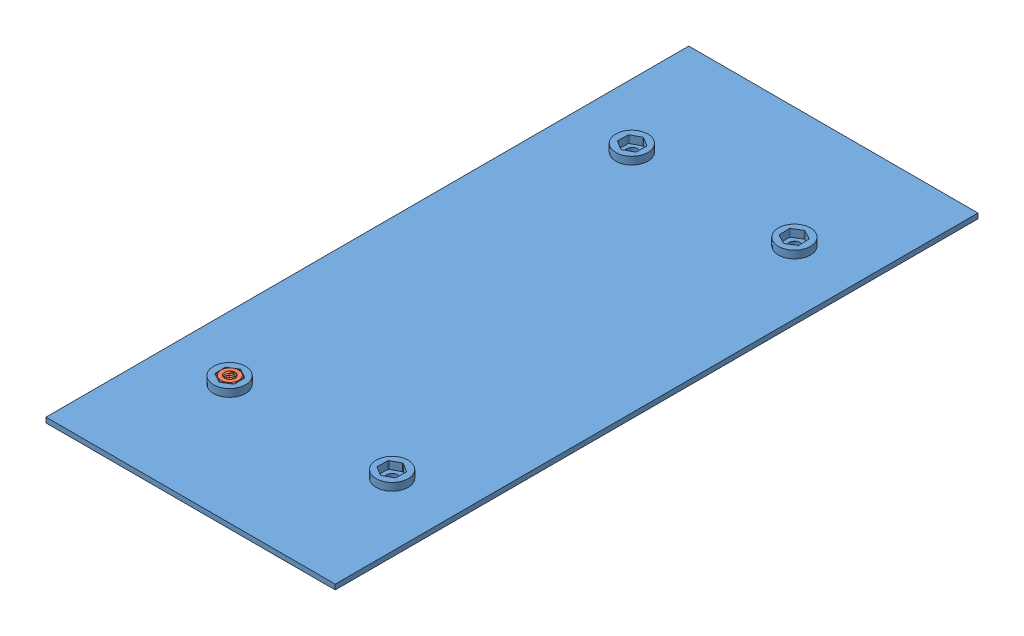
SolidWorks assembly WingAttachment, configuration Default. Lengths in mm.
Overall size (114.3 5.39 254).
2 component instances, 2 part files, 2 mates.
Components (placement in the parent):
- Wing Attachment Plate-1: Wing Attachment Plate [Default] at origin size (114.3 5 254)
- 90592A090_Steel Hex Nut-1: 90592A090_Steel Hex Nut [90592A090] at (25.146 3.575 -47.5074) x (-0.471054 0 0.882104) z (0 -1 0) size (7 8.03 3.62)
Mates (geometry in assembly coordinates):
- Coincident1: coincident anti-aligned: circle of Wing Attachment Plate-1; plane of 90592A090_Steel Hex Nut-1 through (25.146 1.975 -47.5074) normal (0 -1 0)
- Concentric1: concentric aligned: circle of Wing Attachment Plate-1; circle of 90592A090_Steel Hex Nut-1
